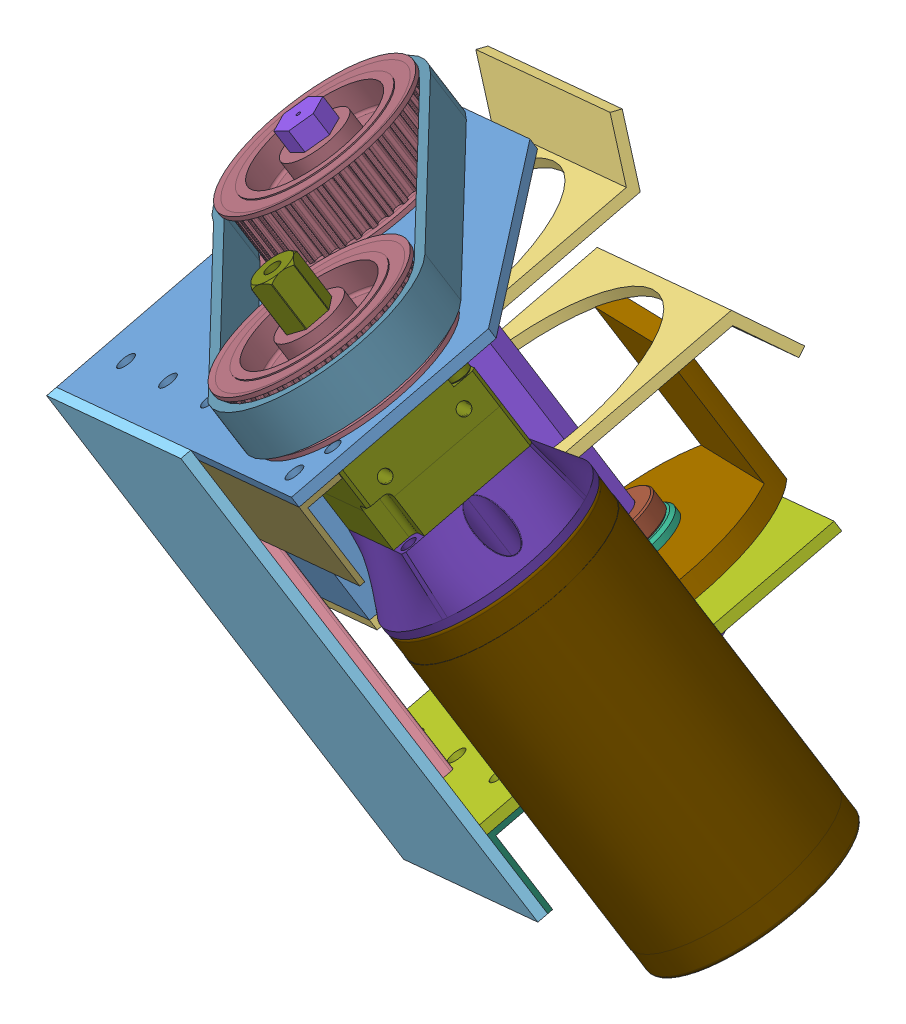
SolidWorks assembly Climber, configuration Default. Lengths in mm.
Overall size (259.09 244.47 218.35).
24 component instances, 19 part files, 60 mates.
Components (placement in the parent):
- Bottom of U Climber Rope guide-1: Bottom of U Climber Rope guide [Default] at (-157.0747 482.7653 -157.004) x (0.827287 0.417969 0.375365) z (-0.179666 -0.436229 0.881717) size (101.6 38.1 12.7)
- NW_02_40_2 carriage-1: NW_02_40_2 carriage [Default] at (-161.0632 473.081 -137.4299) x (-0.827287 -0.417969 -0.375365) z (0.179666 0.436229 -0.881717) size (34 50 11.15)
- Side of U Climber Rope Guide Side-1: Side of U Climber Rope Guide Side [Default] at (-127.4701 513.6384 -121.2934) x (-0.532275 0.796873 0.285792) z (-0.827287 -0.417969 -0.375365) size (20.44 125.48 101.6)
- Side of U Climber Rope Guide Side-2: Side of U Climber Rope Guide Side [Default] at (-191.2428 440.8119 -170.3191) x (0.532275 -0.796873 -0.285792) z (0.827287 0.417969 0.375365) size (20.44 125.48 101.6)
- NS_01_40_200_1rail Climber-1: NS_01_40_200_1rail Climber [Default] at (-122.5493 415.4215 -158.109) x (-0.827287 -0.417969 -0.375365) z (0.179666 0.436229 -0.881717) size (40 101.7 8.7)
- Climber Baseplate-1: Climber Baseplate [Default] at (-145.1092 447.0981 -143.6599) x (0.532275 -0.796873 -0.285792) z (0.179666 0.436229 -0.881717) size (149.22 101.6 3.17)
- Versa Hub 1-2 Hex-1: Versa Hub 1-2 Hex [Default] at (-113.3339 457.8054 -225.6519) x (0.532275 -0.796873 -0.285792) z (0.745852 0.281717 0.603606) size (12.7 55.88 55.88)
- Climber Rope Sideplate-1: Climber Rope Sideplate [Default] at (-109.7663 436.7276 -210.0066) x (-0.827287 -0.417969 -0.375365) z (0.532275 -0.796873 -0.285792) size (101.6 114.3 3.17)
- Climber Hex Shaft-1: Climber Hex Shaft [Default] at (-185.997 566.6161 -186.6283) x (-0.400485 -0.534442 0.744301) z (0.532275 -0.796873 -0.285792) size (14.66 12.7 169.86)
- Climber Rope Winder-1: Climber Rope Winder [Default] at (-168.6001 447.616 -244.6245) x (-0.213591 -0.453075 0.865507) z (0.819184 0.399645 0.411365) size (76.2 50.8 82.55)
- .5 hex bearing 1.125 od-1: .5 hex bearing 1.125 od [Default] at (-106.5616 447.6926 -229.2792) x (-0.719756 -0.603699 0.34278) z (0.445685 -0.023247 0.894888) size (31.12 7.92 31.12)
- 217-2737 Shaft Collar-1: 217-2737 Shaft Collar [Default] at (-114.9461 460.3395 -224.611) x (-0.846169 -0.511195 -0.150588) z (-0.532275 0.796873 0.285792) size (25.39 25.4 7.82)
- 217-2737 Shaft Collar-2: 217-2737 Shaft Collar [Default] at (-100.7122 438.7691 -232.3423) x (-0.846169 -0.511195 -0.150588) z (-0.532275 0.796873 0.285792) size (25.39 25.4 7.82)
- Angle Piece for Climber Side Plate-2: Angle Piece for Climber Side Plate [Default] at (-224.5893 484.1769 -145.1117) x (0.532275 -0.796873 -0.285792) z (0.827287 0.417969 0.375365) size (25.4 25.4 177.8)
- 217-3232 Timing Pulley 36T 15mm-1: 217-3232 Timing Pulley 36T 15mm [Default] at (-176.9155 553.0201 -191.5044) x (0.846538 0.498013 0.188031) z (0.532275 -0.796873 -0.285792) size (60 60 20.5)
- 217-3232 Timing Pulley 36T 15mm-2: 217-3232 Timing Pulley 36T 15mm [Default] at (-101.7464 575.5982 -114.4598) x (-0.806285 -0.580086 0.115783) z (0.532275 -0.796873 -0.285792) size (60 60 20.5)
- Climber Belt 60T (36T pulley)-1: Climber Belt 60T (36T pulley) [Default] at (-118.7586 575.5269 -172.1883) x (-0.499556 -0.568199 0.653907) z (-0.683467 -0.205289 -0.70052) size (64.77 15 174.75)
- .5 hex bearing 1.125 od-3: .5 hex bearing 1.125 od [Default] at (-170.7805 543.8353 -194.7985) x (-0.719756 -0.603699 0.34278) z (0.445685 -0.023247 0.894888) size (31.12 7.92 31.12)
- Angle Piece for Climber Side Plate uncut-1: Angle Piece for Climber Side Plate uncut [Default] at (-160.3704 388.0342 -179.5924) x (0.532275 -0.796873 -0.285792) z (0.827287 0.417969 0.375365) size (25.4 25.4 101.6)
- CIM motor with versa planetary adapter-1: CIM motor with versa planetary adapter [Default] at (-72.6113 594.1735 -57.8326) x (-0.846571 -0.501539 -0.178259) z (0.532275 -0.796873 -0.285792) size (89.57 89.57 206.15)
  - Climber Gearbox for CIM -1: Climber Gearbox for CIM  [Default] at (44.0755 47.0991 70.5278) x (0.976897 0.213712 0) z (0 0 1) size (42 42 70.2)
  - 217-4018 Versa Planetary CIM Adapter-1: 217-4018 Versa Planetary CIM Adapter [Default] at (44.0755 47.0991 69.8528) x (0.976897 0.213712 0) z (-0.213712 0.976897 0) size (64 21.67 64)
  - CIM MOTOR-1: CIM MOTOR [Default] at (44.0755 47.0991 81.3778) x (0 0 1) z (-0.597672 0.801741 0) size (150.2 64.01 64.01)
- Climber Rope Sideplate with motor-1: Climber Rope Sideplate with motor [Default] at (-140.7756 546.2648 -162.1319) x (0.827287 0.417969 0.375365) z (-0.532275 0.796873 0.285792) size (177.8 114.3 3.17)
Mates (geometry in assembly coordinates):
- Concentric1: concentric aligned: cylinder of Bottom of U Climber Rope guide-1 through (-163.7665 487.4099 -147.4275) axis (-0.179666 -0.436229 0.881717) radius 2.9972; cylinder of NW_02_40_2 carriage-1 through (-164.3198 486.0664 -144.7118) axis (-0.179666 -0.436229 0.881717) radius 3
- Parallel2: parallel aligned: plane of Bottom of U Climber Rope guide-1 through (-127.4701 513.6384 -121.2934) normal (0.827287 0.417969 0.375365); plane of NW_02_40_2 carriage-1 through (-159.7942 501.3515 -126.4168) normal (0.827287 0.417969 0.375365)
- Coincident2: coincident anti-aligned: plane of Bottom of U Climber Rope guide-1 through (-159.3564 477.2252 -145.8062) normal (-0.179666 -0.436229 0.881717); plane of NW_02_40_2 carriage-1 through (-146.2291 462.5416 -150.396) normal (0.179666 0.436229 -0.881717)
- Coincident3: coincident anti-aligned: plane of Bottom of U Climber Rope guide-1 through (-211.5224 471.1728 -159.4304) normal (-0.532275 0.796873 0.285792); plane of Side of U Climber Rope Guide Side-1 through (-211.5224 471.1728 -159.4304) normal (0.532275 -0.796873 -0.285792)
- Concentric7: concentric aligned: cylinder of Bottom of U Climber Rope guide-1 through (-136.8357 511.1003 -131.6594) axis (-0.532275 0.796873 0.285792) radius 2.0193; cylinder of Side of U Climber Rope Guide Side-1 through (-138.5257 513.6303 -130.752) axis (-0.532275 0.796873 0.285792) radius 2.4574
- Concentric8: concentric aligned: cylinder of Bottom of U Climber Rope guide-1 through (-199.875 479.2511 -160.2622) axis (-0.532275 0.796873 0.285792) radius 2.0193; cylinder of Side of U Climber Rope Guide Side-1 through (-201.565 481.7811 -159.3548) axis (-0.532275 0.796873 0.285792) radius 2.4574
- Coincident4: coincident anti-aligned: plane of Bottom of U Climber Rope guide-1 through (-191.2428 440.8119 -170.3191) normal (0.532275 -0.796873 -0.285792); plane of Side of U Climber Rope Guide Side-2 through (-107.1904 483.2776 -132.1821) normal (-0.532275 0.796873 0.285792)
- Concentric9: concentric anti-aligned: cylinder of Bottom of U Climber Rope guide-1 through (-136.8357 511.1003 -131.6594) axis (-0.532275 0.796873 0.285792) radius 2.0193; cylinder of Side of U Climber Rope Guide Side-2 through (-114.8661 478.2093 -143.4555) axis (0.532275 -0.796873 -0.285792) radius 2.4574
- Concentric10: concentric anti-aligned: cylinder of Bottom of U Climber Rope guide-1 through (-199.875 479.2511 -160.2622) axis (-0.532275 0.796873 0.285792) radius 2.0193; cylinder of Side of U Climber Rope Guide Side-2 through (-177.9054 446.3601 -172.0582) axis (0.532275 -0.796873 -0.285792) radius 2.4574
- Width1: width anti-aligned: plane of NS_01_40_200_1rail Climber-1 through (-107.0652 424.3844 -154.2621) normal (-0.827287 -0.417969 -0.375365); plane of NS_01_40_200_1rail Climber-1 through (-136.2367 410.8208 -170.7731) normal (0.827287 0.417969 0.375365); plane of NW_02_40_2 carriage-1 through (-159.7942 501.3515 -126.4168) normal (0.827287 0.417969 0.375365); plane of NW_02_40_2 carriage-1 through (-187.1494 489.0164 -142.9706) normal (-0.827287 -0.417969 -0.375365)
- Parallel3: parallel anti-aligned: plane of NW_02_40_2 carriage-1 through (-168.398 497.0047 -130.3206) normal (-0.179666 -0.436229 0.881717); plane of NS_01_40_200_1rail Climber-1 through (-116.8343 419.2761 -158.213) normal (0.179666 0.436229 -0.881717)
- Width2: width anti-aligned: plane of NS_01_40_200_1rail Climber-1 through (-106.7782 425.8767 -157.8885) normal (-0.179666 -0.436229 0.881717); plane of NS_01_40_200_1rail Climber-1 through (-116.8343 419.2761 -158.213) normal (0.179666 0.436229 -0.881717); plane of NW_02_40_2 carriage-1 through (-159.0216 503.2273 -130.2082) normal (0.179666 0.436229 -0.881717); plane of NW_02_40_2 carriage-1 through (-168.398 497.0047 -130.3206) normal (-0.179666 -0.436229 0.881717)
- Coincident5: coincident anti-aligned: plane of NS_01_40_200_1rail Climber-1 through (-106.3813 423.6591 -150.9658) normal (-0.179666 -0.436229 0.881717); plane of Climber Baseplate-1 through (-144.5388 448.4831 -146.4594) normal (0.179666 0.436229 -0.881717)
- Parallel4: parallel aligned: plane of Bottom of U Climber Rope guide-1 through (-127.4701 513.6384 -121.2934) normal (0.827287 0.417969 0.375365); plane of Climber Baseplate-1 through (-142.227 529.1726 -106.0672) normal (0.827287 0.417969 0.375365)
- Coincident7: coincident anti-aligned: plane of Climber Baseplate-1 through (-144.5388 448.4831 -146.4594) normal (0.179666 0.436229 -0.881717); plane of Climber Rope Sideplate-1 through (-76.318 430.4998 -141.4554) normal (-0.179666 -0.436229 0.881717)
- Parallel5: parallel aligned: plane of Climber Baseplate-1 through (-146.8506 367.7936 -186.8515) normal (0.532275 -0.796873 -0.285792); plane of Climber Rope Sideplate-1 through (-108.0763 434.1975 -210.914) normal (0.532275 -0.796873 -0.285792)
- Concentric21: concentric anti-aligned: cylinder of Climber Rope Sideplate-1 through (-105.7504 446.4781 -229.7148) axis (0.532275 -0.796873 -0.285792) radius 14.2875; cylinder of .5 hex bearing 1.125 od-1 through (-102.3434 441.3775 -231.5441) axis (-0.532275 0.796873 0.285792) radius 14.2875
- Coincident14: coincident anti-aligned: plane of Climber Rope Sideplate-1 through (-109.7663 436.7276 -210.0066) normal (-0.532275 0.796873 0.285792); plane of .5 hex bearing 1.125 od-1 through (-105.7504 446.4781 -229.7148) normal (0.532275 -0.796873 -0.285792)
- Coincident16: coincident anti-aligned: plane of Climber Hex Shaft-1 through (-98.8514 431.4277 -241.7352) normal (-0.026096 0.321982 -0.946386); plane of 217-2737 Shaft Collar-1 through (-110.2609 461.8065 -231.0851) normal (0.026096 -0.321982 0.946386)
- Coincident17: coincident anti-aligned: plane of Climber Hex Shaft-1 through (-101.7879 427.509 -236.2778) normal (-0.745852 -0.281717 -0.603606); plane of 217-2737 Shaft Collar-1 through (-116.5894 457.9833 -232.2113) normal (0.745852 0.281717 0.603606)
- Coincident18: coincident anti-aligned: plane of 217-2737 Shaft Collar-2 through (-92.6937 440.0622 -232.1234) normal (-0.719756 -0.603699 0.34278); plane of Climber Hex Shaft-1 through (-92.647 435.1759 -240.6311) normal (0.719756 0.603699 -0.34278)
- Coincident19: coincident anti-aligned: plane of Climber Hex Shaft-1 through (-98.8514 431.4277 -241.7352) normal (-0.026096 0.321982 -0.946386); plane of 217-2737 Shaft Collar-2 through (-96.027 440.2361 -238.8163) normal (0.026096 -0.321982 0.946386)
- Width3: width anti-aligned: plane of NS_01_40_200_1rail Climber-1 through (-104.6201 427.1398 -157.391) normal (0.827287 0.417969 0.375365); plane of NS_01_40_200_1rail Climber-1 through (-138.9693 407.3674 -166.2335) normal (-0.827287 -0.417969 -0.375365); plane of Climber Baseplate-1 through (-226.2793 486.707 -144.2043) normal (-0.827287 -0.417969 -0.375365); plane of Climber Baseplate-1 through (-142.227 529.1726 -106.0672) normal (0.827287 0.417969 0.375365)
- Coincident22: coincident anti-aligned: plane of Versa Hub 1-2 Hex-1 through (-93.94 464.545 -252.7617) normal (0.532275 -0.796873 -0.285792); plane of .5 hex bearing 1.125 od-1 through (-106.5616 447.6926 -229.2792) normal (-0.532275 0.796873 0.285792)
- Coincident23: coincident anti-aligned: plane of Versa Hub 1-2 Hex-1 through (-107.117 461.5611 -224.5455) normal (-0.745852 -0.281717 -0.603606); plane of Climber Hex Shaft-1 through (-89.3791 435.0055 -234.0694) normal (0.745852 0.281717 0.603606)
- Coincident24: coincident anti-aligned: plane of Versa Hub 1-2 Hex-1 through (-110.3915 461.7319 -231.1203) normal (-0.719756 -0.603699 0.34278); plane of Climber Hex Shaft-1 through (-92.647 435.1759 -240.6311) normal (0.719756 0.603699 -0.34278)
- Coincident25: coincident anti-aligned: plane of Climber Hex Shaft-1 through (-92.647 435.1759 -240.6311) normal (0.719756 0.603699 -0.34278); plane of .5 hex bearing 1.125 od-1 through (-99.4069 445.2962 -237.0015) normal (-0.719756 -0.603699 0.34278)
- Coincident26: coincident anti-aligned: plane of Climber Hex Shaft-1 through (-89.3791 435.0055 -234.0694) normal (0.745852 0.281717 0.603606); plane of .5 hex bearing 1.125 od-1 through (-96.139 445.1258 -230.4399) normal (-0.745852 -0.281717 -0.603606)
- Concentric27: concentric aligned: cylinder of Versa Hub 1-2 Hex-1 through (-106.574 447.6851 -229.2814) axis (0.532275 -0.796873 -0.285792) radius 14.2949; cylinder of Climber Rope Winder-1 through (-169.1029 541.2977 -195.7081) axis (0.532275 -0.796873 -0.285792) radius 14.2875
- Coincident28: coincident anti-aligned: plane of Versa Hub 1-2 Hex-1 through (-102.539 457.855 -239.0138) normal (-0.532275 0.796873 0.285792); plane of Climber Rope Winder-1 through (-53.3098 490.317 -237.8403) normal (0.532275 -0.796873 -0.285792)
- Coincident29: coincident anti-aligned: plane of .5 hex bearing 1.125 od-1 through (-102.3434 441.3775 -231.5441) normal (0.532275 -0.796873 -0.285792); plane of 217-2737 Shaft Collar-2 through (-102.4021 441.2991 -231.4349) normal (-0.532275 0.796873 0.285792)
- Coincident31: coincident anti-aligned: plane of Versa Hub 1-2 Hex-1 through (-113.3339 457.8054 -225.6519) normal (-0.532275 0.796873 0.285792); plane of 217-2737 Shaft Collar-1 through (-113.2561 457.8095 -225.5184) normal (0.532275 -0.796873 -0.285792)
- Distance1: distance = 6.35 mm aligned: plane of Climber Hex Shaft-1 through (-95.5835 431.2572 -235.1736) normal (0.532275 -0.796873 -0.285792); plane of 217-2737 Shaft Collar-2 through (-99.0222 436.239 -233.2497) normal (0.532275 -0.796873 -0.285792)
- Coincident38: coincident anti-aligned: plane of Climber Hex Shaft-1 through (-98.8514 431.4277 -241.7352) normal (-0.026096 0.321982 -0.946386); plane of .5 hex bearing 1.125 od-3 through (-169.8303 537.6907 -203.6249) normal (0.026096 -0.321982 0.946386)
- Coincident39: coincident anti-aligned: plane of Climber Hex Shaft-1 through (-98.52 427.3385 -229.7161) normal (-0.719756 -0.603699 0.34278); plane of .5 hex bearing 1.125 od-3 through (-169.4988 533.6015 -191.6058) normal (0.719756 0.603699 -0.34278)
- Distance3: distance = 4.6577 mm anti-aligned: plane of NS_01_40_200_1rail Climber-1 through (-121.8893 417.0238 -161.3478) normal (0.532275 -0.796873 -0.285792); plane of Climber Rope Sideplate-1 through (-109.7663 436.7276 -210.0066) normal (-0.532275 0.796873 0.285792)
- Concentric32: concentric anti-aligned: cylinder of 217-3232 Timing Pulley 36T 15mm-1 through (-207.7783 599.225 -174.9334) axis (0.532275 -0.796873 -0.285792) radius 20.5; cylinder of .5 hex bearing 1.125 od-3 through (-169.9693 542.6209 -195.234) axis (-0.532275 0.796873 0.285792) radius 15.5575
- Concentric35: concentric aligned: cylinder of Climber Rope Sideplate-1 through (-115.7772 415.4996 -173.1214) axis (0.532275 -0.796873 -0.285792) radius 2.8067; cylinder of Angle Piece for Climber Side Plate uncut-1 through (-114.9255 414.2245 -173.5787) axis (0.532275 -0.796873 -0.285792) radius 2.4574
- Coincident50: coincident anti-aligned: plane of Climber Baseplate-1 through (-144.5388 448.4831 -146.4594) normal (0.179666 0.436229 -0.881717); plane of Angle Piece for Climber Side Plate uncut-1 through (-62.7983 410.2592 -148.7145) normal (-0.179666 -0.436229 0.881717)
- Coincident51: coincident anti-aligned: plane of Climber Rope Sideplate-1 through (-108.0763 434.1975 -210.914) normal (0.532275 -0.796873 -0.285792); plane of Angle Piece for Climber Side Plate uncut-1 through (-76.318 430.4998 -141.4554) normal (-0.532275 0.796873 0.285792)
- Coincident52: coincident aligned: plane of Climber Baseplate-1 through (-146.8506 367.7936 -186.8515) normal (0.532275 -0.796873 -0.285792); plane of Angle Piece for Climber Side Plate uncut-1 through (-62.5108 410.9573 -150.1254) normal (0.532275 -0.796873 -0.285792)
- Coincident56: coincident anti-aligned: plane of Climber Baseplate-1 through (-144.5388 448.4831 -146.4594) normal (0.179666 0.436229 -0.881717); plane of Angle Piece for Climber Side Plate-2 through (-63.9779 538.2512 -85.631) normal (-0.179666 -0.436229 0.881717)
- Coincident61: coincident anti-aligned: plane of 217-3232 Timing Pulley 36T 15mm-2 through (-94.652 566.3584 -111.3486) normal (-0.258048 0.168801 -0.951271); plane of CIM motor with versa planetary adapter-1/Climber Gearbox for CIM -1 through (-116.7167 592.8396 -100.6641) normal (0.258048 -0.168801 0.951271)
- Coincident62: coincident anti-aligned: plane of 217-3232 Timing Pulley 36T 15mm-2 through (-91.0373 570.0843 -115.0056) normal (-0.827287 -0.417969 -0.375365); plane of CIM motor with versa planetary adapter-1/Climber Gearbox for CIM -1 through (-110.8048 597.093 -101.5131) normal (0.827287 0.417969 0.375365)
- Coincident65: coincident anti-aligned: plane of Climber Baseplate-1 through (-144.5388 448.4831 -146.4594) normal (0.179666 0.436229 -0.881717); plane of Climber Rope Sideplate with motor-1 through (-226.2793 486.707 -144.2043) normal (-0.179666 -0.436229 0.881717)
- Coincident66: coincident anti-aligned: plane of Angle Piece for Climber Side Plate-2 through (-77.4977 558.4918 -78.3718) normal (-0.532275 0.796873 0.285792); plane of Climber Rope Sideplate with motor-1 through (-140.7756 546.2648 -162.1319) normal (0.532275 -0.796873 -0.285792)
- Concentric36: concentric aligned: cylinder of .5 hex bearing 1.125 od-3 through (-169.9693 542.6209 -195.234) axis (-0.532275 0.796873 0.285792) radius 15.5575; cylinder of Climber Rope Sideplate with motor-1 through (-168.2794 540.0908 -196.1414) axis (-0.532275 0.796873 0.285792) radius 14.2875
- Concentric38: concentric anti-aligned: cylinder of CIM motor with versa planetary adapter-1/Climber Gearbox for CIM -1 through (-73.1619 549.8898 -100.9844) axis (0.532275 -0.796873 -0.285792) radius 2.0193; cylinder of Climber Rope Sideplate with motor-1 through (-81.4787 562.341 -96.5189) axis (-0.532275 0.796873 0.285792) radius 2.4892
- Concentric45: concentric aligned: cylinder of CIM motor with versa planetary adapter-1/Climber Gearbox for CIM -1 through (-93.0438 562.5695 -119.1324) axis (-0.532275 0.796873 0.285792) radius 8.5; cylinder of Climber Rope Sideplate with motor-1 through (-93.1103 562.6689 -119.0968) axis (-0.532275 0.796873 0.285792) radius 14.2875
- Coincident67: coincident anti-aligned: plane of CIM motor with versa planetary adapter-1/Climber Gearbox for CIM -1 through (-71.9642 580.6071 -129.7302) normal (-0.532275 0.796873 0.285792); plane of Climber Rope Sideplate with motor-1 through (-140.7756 546.2648 -162.1319) normal (0.532275 -0.796873 -0.285792)
- Coincident68: coincident: plane of Climber Baseplate-1 through (-226.2793 486.707 -144.2043) normal (-0.827287 -0.417969 -0.375365); line of Angle Piece for Climber Side Plate-2 through (-223.4501 483.5998 -146.9799) axis (0.532275 -0.796873 -0.285792)
- Coincident70: coincident aligned: plane of Climber Baseplate-1 through (-226.2793 486.707 -144.2043) normal (-0.532275 0.796873 0.285792); plane of Climber Rope Sideplate with motor-1 through (-142.4656 548.7949 -161.2245) normal (-0.532275 0.796873 0.285792)
- Coincident71: coincident aligned: plane of Climber Baseplate-1 through (-226.2793 486.707 -144.2043) normal (-0.827287 -0.417969 -0.375365); plane of Climber Rope Sideplate with motor-1 through (-205.7435 536.568 -244.9845) normal (-0.827287 -0.417969 -0.375365)
- Concentric46: concentric aligned: cylinder of 217-3232 Timing Pulley 36T 15mm-1 through (-176.9155 553.0201 -191.5044) axis (0.532275 -0.796873 -0.285792) radius 30; cylinder of Climber Belt 60T (36T pulley)-1 through (-180.9076 558.9966 -189.361) axis (0.532275 -0.796873 -0.285792) radius 29.21
- Concentric49: concentric aligned: cylinder of 217-3232 Timing Pulley 36T 15mm-2 through (-101.7464 575.5982 -114.4598) axis (0.532275 -0.796873 -0.285792) radius 30; cylinder of Climber Belt 60T (36T pulley)-1 through (-105.7385 581.5747 -112.3164) axis (0.532275 -0.796873 -0.285792) radius 29.21
- Width4: width aligned: plane of 217-3232 Timing Pulley 36T 15mm-1 through (-171.6593 545.151 -194.3266) normal (0.532275 -0.796873 -0.285792); plane of 217-3232 Timing Pulley 36T 15mm-1 through (-182.1717 560.8892 -188.6822) normal (-0.532275 0.796873 0.285792); plane of Climber Belt 60T (36T pulley)-1 through (-97.7544 569.6217 -116.6032) normal (0.532275 -0.796873 -0.285792); plane of Climber Belt 60T (36T pulley)-1 through (-105.7385 581.5747 -112.3164) normal (-0.532275 0.796873 0.285792)
- Width5: width anti-aligned: plane of 217-3232 Timing Pulley 36T 15mm-2 through (-96.4902 567.7291 -117.282) normal (0.532275 -0.796873 -0.285792); plane of 217-3232 Timing Pulley 36T 15mm-2 through (-107.0026 583.4673 -111.6376) normal (-0.532275 0.796873 0.285792); plane of Climber Belt 60T (36T pulley)-1 through (-105.7385 581.5747 -112.3164) normal (-0.532275 0.796873 0.285792); plane of Climber Belt 60T (36T pulley)-1 through (-97.7544 569.6217 -116.6032) normal (0.532275 -0.796873 -0.285792)
- Concentric50: concentric aligned: cylinder of .5 hex bearing 1.125 od-3 through (-166.5623 537.5203 -197.0633) axis (-0.532275 0.796873 0.285792) radius 14.2875; cylinder of Climber Rope Sideplate with motor-1 through (-168.2794 540.0908 -196.1414) axis (-0.532275 0.796873 0.285792) radius 14.2875
- Coincident73: coincident anti-aligned: plane of .5 hex bearing 1.125 od-3 through (-169.9693 542.6209 -195.234) normal (0.532275 -0.796873 -0.285792); plane of Climber Rope Sideplate with motor-1 through (-142.4656 548.7949 -161.2245) normal (-0.532275 0.796873 0.285792)
- Distance6: distance = 3.175 mm anti-aligned: plane of 217-3232 Timing Pulley 36T 15mm-2 through (-96.4902 567.7291 -117.282) normal (0.532275 -0.796873 -0.285792); plane of Climber Rope Sideplate with motor-1 through (-142.4656 548.7949 -161.2245) normal (-0.532275 0.796873 0.285792)
